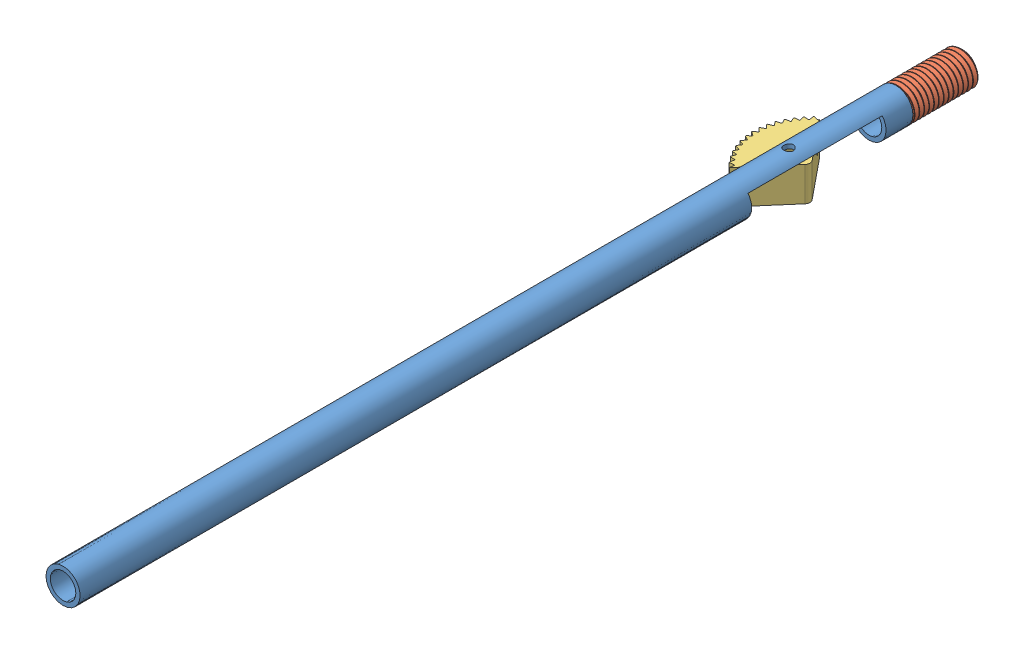
SolidWorks assembly handle assembly, configuration Default. Lengths in mm.
Overall size (32.71 9.89 168.49).
3 component instances, 3 part files, 2 mates.
Components (placement in the parent):
- handle-1: handle [Default] at (54.5898 76.9012 45.9082) size (6.35 6.35 155)
- handle threads-1: handle threads [92562A141] at (54.5898 76.9012 33.2082) x (-0.616641 -0.787245 0) z (0 0 -1) size (7.33 6.67 13.92)
- wedge v-5 14-Sep-2017_5mm-1: wedge v-5 14-Sep-2017_5mm [Default] at (54.6655 75.7262 56.6208) x (-0.194078 0 -0.980986) z (0 1 0) size (31.24 27.17 6.35)
Mates (geometry in assembly coordinates):
- Coincident2: coincident aligned: circle of handle-1; circle of handle threads-1
- Coincident3: coincident anti-aligned: plane of handle-1 through (54.5898 78.9012 45.9082) normal (0 -1 0); plane of wedge v-5 14-Sep-2017_5mm-1 through (58.4124 78.9012 65.3033) normal (0 1 0)
